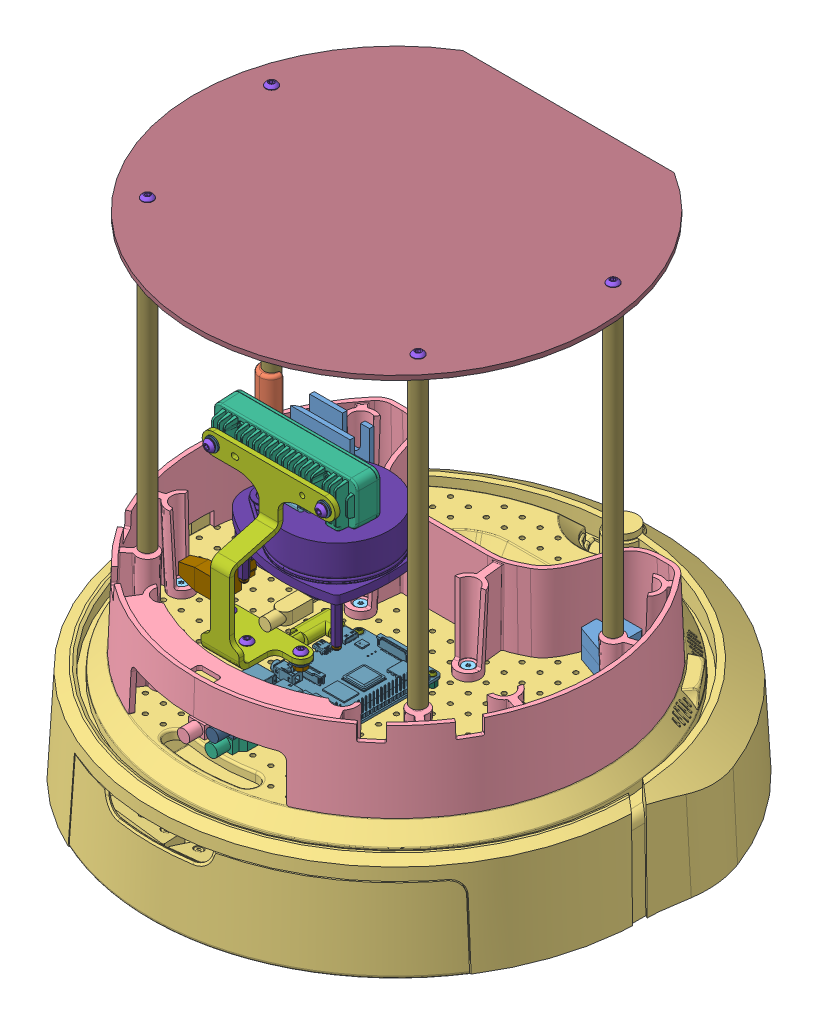
SolidWorks assembly mount_and_robot, configuration Default. Lengths in mm.
Overall size (344.21 352.66 342.43).
70 component instances, 28 part files, 2 mates.
Components (placement in the parent):
- BMP_camera_holder-1: BMP_camera_holder [Default] at (-168.9994 30.2674 -23.0245) x (-1 0 0) z (0 0 -1) size (60 40 38)
  - IR_camera-1: IR_camera [Default] at (-89.6669 -4.8675 17.6343) size (40 24 16)
  - pressure_sensor_holder-1: pressure_sensor_holder [Default] at (-44.6669 -4.8675 1.6343) x (-1 0 0) z (0 0 -1) size (50 40 22)
- turtlebot4_official.STEP-1: turtlebot4_official.STEP [Default] at (-17.5555 -120.5556 6.041) x (0.000609 0 -1) z (0 1 0) size (342.22 344 352.66)
  - 026292-OS_1__Item Name from PLM.STEP-1: 026292-OS_1__Item Name from PLM.STEP [Default] at (0 0 37.8855) x (0 1 0) z (1 0 0) size (344 96.08 342.22)
  - 025441_4_Riser Bracket-O275, Plastic, Black.STEP-1: 025441_4_Riser Bracket-O275, Plastic, Black.STEP [Default] at (0.0007 -0.0149 93.3855) size (229.59 273.19 53.38)
  - 025614_1_Screw, Cap, Flat Head-M3.5 X 10, Steal, Zinc Plate.STEP-1: 025614_1_Screw, Cap, Flat Head-M3.5 X 10, Steal, Zinc Plate.STEP [Default] at (72 96 92.546) x (0.995283 0.09701 0) z (0 0 1) size (7.3 7.3 10.01)
  - 025614_1_Screw, Cap, Flat Head-M3.5 X 10, Steal, Zinc Plate.STEP-2: 025614_1_Screw, Cap, Flat Head-M3.5 X 10, Steal, Zinc Plate.STEP [Default] at (12 36 92.546) x (0.967312 0.253588 0) z (0 0 1) size (7.3 7.3 10.01)
  - 025614_1_Screw, Cap, Flat Head-M3.5 X 10, Steal, Zinc Plate.STEP-3: 025614_1_Screw, Cap, Flat Head-M3.5 X 10, Steal, Zinc Plate.STEP [Default] at (12 -36 92.546) x (0.544294 -0.838895 0) z (0 0 1) size (7.3 7.3 10.01)
  - 025614_1_Screw, Cap, Flat Head-M3.5 X 10, Steal, Zinc Plate.STEP-4: 025614_1_Screw, Cap, Flat Head-M3.5 X 10, Steal, Zinc Plate.STEP [Default] at (72 -96 92.546) x (0.325351 0.945593 0) z (0 0 1) size (7.3 7.3 10.01)
  - 025614_1_Screw, Cap, Flat Head-M3.5 X 10, Steal, Zinc Plate.STEP-5: 025614_1_Screw, Cap, Flat Head-M3.5 X 10, Steal, Zinc Plate.STEP [Default] at (-36 -108 92.546) x (0.804099 0.594496 0) z (0 0 1) size (7.3 7.3 10.01)
  - 025614_1_Screw, Cap, Flat Head-M3.5 X 10, Steal, Zinc Plate.STEP-6: 025614_1_Screw, Cap, Flat Head-M3.5 X 10, Steal, Zinc Plate.STEP [Default] at (-96 -60 92.546) x (0.770543 0.637388 0) z (0 0 1) size (7.3 7.3 10.01)
  - 025614_1_Screw, Cap, Flat Head-M3.5 X 10, Steal, Zinc Plate.STEP-7: 025614_1_Screw, Cap, Flat Head-M3.5 X 10, Steal, Zinc Plate.STEP [Default] at (-96 60 92.546) x (0.764306 0.644854 0) z (0 0 1) size (7.3 7.3 10.01)
  - 025961_1_Camera, RGBD, Luxonis OAK-D-Pro.STEP-1: 025961_1_Camera, RGBD, Luxonis OAK-D-Pro.STEP [Default] at (-69.2695 -44.509 249.7055) x (0.00006 1 0) z (1 -0.00006 0) size (97.03 29.53 22.93)
  - 025426_6_Bracket, Camera, Aluminium Alloy.STEP-1: 025426_6_Bracket, Camera, Aluminium Alloy.STEP [Default] at (-118.0061 -0.0061 145.9555) x (1 -0.00006 0) z (0 0 1) size (36 89 99)
  - 025609_1_Screw, Cap, Round Head-M4x0.7 X 10, Stainless Steel Type 18-8, Black Oxide.STEP-1: 025609_1_Screw, Cap, Round Head-M4x0.7 X 10, Stainless Steel Type 18-8, Black Oxide.STEP [Default] at (-88.0075 -24.0078 145.3155) x (0.93747 0.348067 0) z (0 0 1) size (7.6 7.6 12.21)
  - 025609_1_Screw, Cap, Round Head-M4x0.7 X 10, Stainless Steel Type 18-8, Black Oxide.STEP-2: 025609_1_Screw, Cap, Round Head-M4x0.7 X 10, Stainless Steel Type 18-8, Black Oxide.STEP [Default] at (-100.0061 -0.0071 145.3155) x (0.79095 0.61188 0) z (0 0 1) size (7.6 7.6 12.21)
  - 025609_1_Screw, Cap, Round Head-M4x0.7 X 10, Stainless Steel Type 18-8, Black Oxide.STEP-3: 025609_1_Screw, Cap, Round Head-M4x0.7 X 10, Stainless Steel Type 18-8, Black Oxide.STEP [Default] at (-88.0046 23.9922 145.3155) x (0.731026 0.682349 0) z (0 0 1) size (7.6 7.6 12.21)
  - 010898_Nut, Hex-M4 x 0.7 X 3.2, Type 18-8 Stainless Steel.STEP-1: 010898_Nut, Hex-M4 x 0.7 X 3.2, Type 18-8 Stainless Steel.STEP [Default] at (-100.0061 -0.0071 141.8855) x (0.923728 0.383049 0) z (0 0 -1) size (8.09 8.1 3.22)
  - 025610_1_Washer, Flat-O4.3 X O9 X 0.9, Stainless Steel, Black Oxide.STEP-1: 025610_1_Washer, Flat-O4.3 X O9 X 0.9, Stainless Steel, Black Oxide.STEP [Default] at (-100.0061 -0.0071 144.3855) x (-0.923728 -0.383049 0) z (0 0 -1) size (9 9 0.9)
  - 010898_Nut, Hex-M4 x 0.7 X 3.2, Type 18-8 Stainless Steel.STEP-2: 010898_Nut, Hex-M4 x 0.7 X 3.2, Type 18-8 Stainless Steel.STEP [Default] at (-88.0075 -24.0078 141.8855) x (0.85131 0.524663 0) z (0 0 -1) size (8.09 8.1 3.22)
  - 025610_1_Washer, Flat-O4.3 X O9 X 0.9, Stainless Steel, Black Oxide.STEP-2: 025610_1_Washer, Flat-O4.3 X O9 X 0.9, Stainless Steel, Black Oxide.STEP [Default] at (-88.0075 -24.0078 144.3855) x (-0.85131 -0.524663 0) z (0 0 -1) size (9 9 0.9)
  - 010898_Nut, Hex-M4 x 0.7 X 3.2, Type 18-8 Stainless Steel.STEP-3: 010898_Nut, Hex-M4 x 0.7 X 3.2, Type 18-8 Stainless Steel.STEP [Default] at (-88.0046 23.9922 141.8855) x (0.777574 0.628792 0) z (0 0 -1) size (8.09 8.1 3.22)
  - 025610_1_Washer, Flat-O4.3 X O9 X 0.9, Stainless Steel, Black Oxide.STEP-3: 025610_1_Washer, Flat-O4.3 X O9 X 0.9, Stainless Steel, Black Oxide.STEP [Default] at (-88.0046 23.9922 144.3855) x (-0.777574 -0.628792 0) z (0 0 -1) size (9 9 0.9)
  - 025609_1_Screw, Cap, Round Head-M4x0.7 X 10, Stainless Steel Type 18-8, Black Oxide.STEP-4: 025609_1_Screw, Cap, Round Head-M4x0.7 X 10, Stainless Steel Type 18-8, Black Oxide.STEP [Default] at (-83.6246 37.4919 237.9555) x (0.000005 0.080023 0.996793) z (-1 0.00006 0) size (7.6 7.6 12.21)
  - 025609_1_Screw, Cap, Round Head-M4x0.7 X 10, Stainless Steel Type 18-8, Black Oxide.STEP-5: 025609_1_Screw, Cap, Round Head-M4x0.7 X 10, Stainless Steel Type 18-8, Black Oxide.STEP [Default] at (-83.6291 -37.5081 237.9555) x (0.000033 0.560382 -0.828234) z (-1 0.00006 0) size (7.6 7.6 12.21)
  - 025610_1_Washer, Flat-O4.3 X O9 X 0.9, Stainless Steel, Black Oxide.STEP-4: 025610_1_Washer, Flat-O4.3 X O9 X 0.9, Stainless Steel, Black Oxide.STEP [Default] at (-86.4246 37.4921 237.9555) x (-0.000007 -0.116927 -0.993141) z (1 -0.00006 0) size (9 9 0.9)
  - 025610_1_Washer, Flat-O4.3 X O9 X 0.9, Stainless Steel, Black Oxide.STEP-5: 025610_1_Washer, Flat-O4.3 X O9 X 0.9, Stainless Steel, Black Oxide.STEP [Default] at (-86.4291 -37.5079 237.9555) x (-0.000002 -0.035095 -0.999384) z (1 -0.00006 0) size (9 9 0.9)
  - 026387_1_Washer, Locking, Split-DIN 7980 M4 X 1.1, Steel, Black.STEP-1: 026387_1_Washer, Locking, Split-DIN 7980 M4 X 1.1, Steel, Black.STEP [Default] at (-87.5246 37.4921 237.9555) x (0 0.00006 -1) z (1 -0.00006 0) size (7 7 2.31)
  - 026387_1_Washer, Locking, Split-DIN 7980 M4 X 1.1, Steel, Black.STEP-2: 026387_1_Washer, Locking, Split-DIN 7980 M4 X 1.1, Steel, Black.STEP [Default] at (-87.5291 -37.5079 237.9555) x (0 0.00006 -1) z (1 -0.00006 0) size (7 7 2.31)
  - 025481_4_Standoff, Threaded, Round-Male-Female, M4 X 200, Aluminum.STEP-1: 025481_4_Standoff, Threaded, Round-Male-Female, M4 X 200, Aluminum.STEP [Default] at (30.6302 114.2957 241.9555) x (0 0 -1) z (-0.212288 0.977207 0) size (208 10 10)
  - 025481_4_Standoff, Threaded, Round-Male-Female, M4 X 200, Aluminum.STEP-2: 025481_4_Standoff, Threaded, Round-Male-Female, M4 X 200, Aluminum.STEP [Default] at (-76.0687 90.6411 241.9555) x (0 0 -1) z (-0.247385 -0.968917 0) size (208 10 10)
  - 025481_4_Standoff, Threaded, Round-Male-Female, M4 X 200, Aluminum.STEP-3: 025481_4_Standoff, Threaded, Round-Male-Female, M4 X 200, Aluminum.STEP [Default] at (30.6302 -114.2957 241.9555) x (0 0 -1) z (0.68149 -0.731827 0) size (208 10 10)
  - 025481_4_Standoff, Threaded, Round-Male-Female, M4 X 200, Aluminum.STEP-4: 025481_4_Standoff, Threaded, Round-Male-Female, M4 X 200, Aluminum.STEP [Default] at (-76.0687 -90.6411 241.9555) x (0 0 -1) z (0.57449 0.818512 0) size (208 10 10)
  - 025394_Plate, Sensor Integration.STEP-1: 025394_Plate, Sensor Integration.STEP [Default] at (0.0007 -0.0149 345.9555) size (250 270 3)
  - 025609_1_Screw, Cap, Round Head-M4x0.7 X 10, Stainless Steel Type 18-8, Black Oxide.STEP-6: 025609_1_Screw, Cap, Round Head-M4x0.7 X 10, Stainless Steel Type 18-8, Black Oxide.STEP [Default] at (30.6302 114.2957 345.0555) size (7.6 7.6 12.21)
  - 025609_1_Screw, Cap, Round Head-M4x0.7 X 10, Stainless Steel Type 18-8, Black Oxide.STEP-7: 025609_1_Screw, Cap, Round Head-M4x0.7 X 10, Stainless Steel Type 18-8, Black Oxide.STEP [Default] at (30.6302 -114.2957 345.0555) x (0.987351 0.158553 0) z (0 0 1) size (7.6 7.6 12.21)
  - 025609_1_Screw, Cap, Round Head-M4x0.7 X 10, Stainless Steel Type 18-8, Black Oxide.STEP-8: 025609_1_Screw, Cap, Round Head-M4x0.7 X 10, Stainless Steel Type 18-8, Black Oxide.STEP [Default] at (-76.0687 -90.6411 345.0555) x (0.959125 0.282984 0) z (0 0 1) size (7.6 7.6 12.21)
  - 025609_1_Screw, Cap, Round Head-M4x0.7 X 10, Stainless Steel Type 18-8, Black Oxide.STEP-9: 025609_1_Screw, Cap, Round Head-M4x0.7 X 10, Stainless Steel Type 18-8, Black Oxide.STEP [Default] at (-76.0687 90.6411 345.0555) x (0.928571 0.371154 0) z (0 0 1) size (7.6 7.6 12.21)
  - 024051_1_Computer, Single Board, SBC-Raspberry Pi 4, 2 GB.STEP-1: 024051_1_Computer, Single Board, SBC-Raspberry Pi 4, 2 GB.STEP [Default] at (-46.6082 -7.1031 99.1855) x (-1 0 0) z (0 1 0) size (89 19.93 58.4)
  - 025552_2_Standoff, Threaded, Hex - Male-Female, M2.5 X 5, Hex Size 4.5 mm, Aluminum.STEP-1: 025552_2_Standoff, Threaded, Hex - Male-Female, M2.5 X 5, Hex Size 4.5 mm, Aluminum.STEP [Default] at (-7.6082 17.3969 93.9355) x (0 0 -1) z (-0.895183 -0.445699 0) size (8.9 5.21 4.51)
  - 025552_2_Standoff, Threaded, Hex - Male-Female, M2.5 X 5, Hex Size 4.5 mm, Aluminum.STEP-2: 025552_2_Standoff, Threaded, Hex - Male-Female, M2.5 X 5, Hex Size 4.5 mm, Aluminum.STEP [Default] at (-65.6082 -31.6031 93.9455) x (0 0 -1) z (-0.813193 -0.581995 0) size (8.9 5.21 4.51)
  - 025552_2_Standoff, Threaded, Hex - Male-Female, M2.5 X 5, Hex Size 4.5 mm, Aluminum.STEP-3: 025552_2_Standoff, Threaded, Hex - Male-Female, M2.5 X 5, Hex Size 4.5 mm, Aluminum.STEP [Default] at (-7.6082 -31.6031 93.9355) x (0 0 -1) z (-0.813193 -0.581995 0) size (8.9 5.21 4.51)
  - 025552_2_Standoff, Threaded, Hex - Male-Female, M2.5 X 5, Hex Size 4.5 mm, Aluminum.STEP-4: 025552_2_Standoff, Threaded, Hex - Male-Female, M2.5 X 5, Hex Size 4.5 mm, Aluminum.STEP [Default] at (-65.6082 17.3969 93.9355) x (0 0 -1) z (-0.813193 -0.581995 0) size (8.9 5.21 4.51)
  - 025616_1_Screw, Cap, Round Head-M2.5x0.45 X 4, Stainless Steel Type 18-8, Black Oxide.STEP-1: 025616_1_Screw, Cap, Round Head-M2.5x0.45 X 4, Stainless Steel Type 18-8, Black Oxide.STEP [Default] at (-65.6082 17.3969 101.4755) x (-0.922007 -0.387173 0) z (0 0 1) size (4.5 4.5 5.5)
  - 025616_1_Screw, Cap, Round Head-M2.5x0.45 X 4, Stainless Steel Type 18-8, Black Oxide.STEP-2: 025616_1_Screw, Cap, Round Head-M2.5x0.45 X 4, Stainless Steel Type 18-8, Black Oxide.STEP [Default] at (-65.6082 -31.6031 101.4755) x (-0.848957 -0.528462 0) z (0 0 1) size (4.5 4.5 5.5)
  - 025616_1_Screw, Cap, Round Head-M2.5x0.45 X 4, Stainless Steel Type 18-8, Black Oxide.STEP-3: 025616_1_Screw, Cap, Round Head-M2.5x0.45 X 4, Stainless Steel Type 18-8, Black Oxide.STEP [Default] at (-7.6082 17.3969 101.4755) x (-0.774756 -0.63226 0) z (0 0 1) size (4.5 4.5 5.5)
  - 025616_1_Screw, Cap, Round Head-M2.5x0.45 X 4, Stainless Steel Type 18-8, Black Oxide.STEP-4: 025616_1_Screw, Cap, Round Head-M2.5x0.45 X 4, Stainless Steel Type 18-8, Black Oxide.STEP [Default] at (-7.6082 -31.6031 101.4755) x (-0.712449 -0.701724 0) z (0 0 1) size (4.5 4.5 5.5)
  - 025962_1_LIDAR, RPLidar A1M8, Slamtec.STEP-1: 025962_1_LIDAR, RPLidar A1M8, Slamtec.STEP [Default] at (-76.5474 -37.1117 145.9555) x (0.00006 1 0) z (1 -0.00006 0) size (97.35 55.07 71.45)
  - 026634_1_Screw, Cap, Socket Head-M2.5x0.45 X 6, Stainless Steel Type 316.STEP-1: 026634_1_Screw, Cap, Socket Head-M2.5x0.45 X 6, Stainless Steel Type 316.STEP [Default] at (-12.0078 -28.0124 142.8855) x (-0.959321 -0.282317 0) z (0 0 -1) size (4.7 4.7 7.5)
  - 026634_1_Screw, Cap, Socket Head-M2.5x0.45 X 6, Stainless Steel Type 316.STEP-2: 026634_1_Screw, Cap, Socket Head-M2.5x0.45 X 6, Stainless Steel Type 316.STEP [Default] at (-20.0036 41.9881 142.8855) x (-0.902424 -0.430849 0) z (0 0 -1) size (4.7 4.7 7.5)
  - 026634_1_Screw, Cap, Socket Head-M2.5x0.45 X 6, Stainless Steel Type 316.STEP-3: 026634_1_Screw, Cap, Socket Head-M2.5x0.45 X 6, Stainless Steel Type 316.STEP [Default] at (-60.0036 41.9905 142.8855) x (-0.840218 -0.542249 0) z (0 0 -1) size (4.7 4.7 7.5)
  - 026634_1_Screw, Cap, Socket Head-M2.5x0.45 X 6, Stainless Steel Type 316.STEP-4: 026634_1_Screw, Cap, Socket Head-M2.5x0.45 X 6, Stainless Steel Type 316.STEP [Default] at (-68.0078 -28.009 142.8855) x (-0.786015 -0.618207 0) z (0 0 -1) size (4.7 4.7 7.5)
  - Create3 Weight Pack_Item Name from PLM.STEP-1: Create3 Weight Pack_Item Name from PLM.STEP [Default] at (193.0236 145.8095 86.626) x (0.225602 -0.97422 0) z (0.959419 0.222174 -0.173648) size (48.09 14.03 30.89)
  - Create3 Weight Pack_Item Name from PLM.STEP-2: Create3 Weight Pack_Item Name from PLM.STEP [Default] at (193.0236 145.8095 95.626) x (0.225602 -0.97422 0) z (0.959419 0.222174 -0.173648) size (48.09 14.03 30.89)
  - Create3 Weight Pack_Item Name from PLM.STEP-3: Create3 Weight Pack_Item Name from PLM.STEP [Default] at (194.4529 -142.3863 109.1449) x (0.200558 0.979682 0) z (0.964798 -0.197511 0.173648) size (48.09 14.03 30.89)
  - Create3 Weight Pack_Item Name from PLM.STEP-4: Create3 Weight Pack_Item Name from PLM.STEP [Default] at (194.4529 -142.3863 118.1449) x (0.200558 0.979682 0) z (0.964798 -0.197511 0.173648) size (48.09 14.03 30.89)
  - 025740_1_Nut, Hex-M2.5 x 0.45 X 2.1, Steel Class 8, Zinc Plate.STEP-1: 025740_1_Nut, Hex-M2.5 x 0.45 X 2.1, Steel Class 8, Zinc Plate.STEP [Default] at (-65.6082 17.3969 89.6355) size (5.78 5.78 2.01)
  - 025740_1_Nut, Hex-M2.5 x 0.45 X 2.1, Steel Class 8, Zinc Plate.STEP-2: 025740_1_Nut, Hex-M2.5 x 0.45 X 2.1, Steel Class 8, Zinc Plate.STEP [Default] at (-65.6082 -31.6031 89.6355) size (5.78 5.78 2.01)
  - 025740_1_Nut, Hex-M2.5 x 0.45 X 2.1, Steel Class 8, Zinc Plate.STEP-3: 025740_1_Nut, Hex-M2.5 x 0.45 X 2.1, Steel Class 8, Zinc Plate.STEP [Default] at (-7.6082 -31.6031 89.6355) size (5.78 5.78 2.01)
  - 025740_1_Nut, Hex-M2.5 x 0.45 X 2.1, Steel Class 8, Zinc Plate.STEP-4: 025740_1_Nut, Hex-M2.5 x 0.45 X 2.1, Steel Class 8, Zinc Plate.STEP [Default] at (-7.6082 17.3969 89.6355) x (-0.997343 0.072845 0) z (0 0 1) size (5.78 5.78 2.01)
  - 025614_1_Screw, Cap, Flat Head-M3.5 X 10, Steal, Zinc Plate.STEP-8: 025614_1_Screw, Cap, Flat Head-M3.5 X 10, Steal, Zinc Plate.STEP [Default] at (-36 108 92.546) x (0.652394 0.75788 0) z (0 0 1) size (7.3 7.3 10.01)
  - 025944_2_Micro B ONLY.STEP-1: 025944_2_Micro B ONLY.STEP [Default] at (-205.6815 -7.5008 160.7555) x (0.00006 1 0) z (0 0 1) size (10 32.6 8.01)
  - 025944_2_USB A ONLY.STEP-1: 025944_2_USB A ONLY.STEP [Default] at (-240.7332 11.8969 103.9655) x (0 1 0) z (0 0 -1) size (16.5 47.05 8.45)
  - 025941_2_90 Deg ONLY.STEP-1: 025941_2_90 Deg ONLY.STEP [Default] at (-66.0541 -121.4542 215.4267) x (0 0 1) z (1 -0.00006 0) size (21.1 29 7)
  - 025941_2_USB A ONLY.STEP-1: 025941_2_USB A ONLY.STEP [Default] at (-242.0532 -6.1031 104.1255) x (0 -1 0) z (0 0 1) size (16.5 47.05 8.45)
  - 025942_1_90 Deg ONLY.STEP-1: 025942_1_90 Deg ONLY.STEP [Default] at (-155.8082 32.7969 101.5655) x (0 -1 0) z (0 0 -1) size (21.1 29 7)
  - 025942_1_USB C ONLY.STEP-1: 025942_1_USB C ONLY.STEP [Default] at (-220.2485 -60.2044 70.0453) x (0.000224 1 0) z (0 0 -1) size (13 36 7)
  - 025943_1_USB B ONLY.STEP-1: 025943_1_USB B ONLY.STEP [Default] at (-65.4395 138.7324 138.0655) x (1 -0.000138 0) z (0 0 1) size (28 26.85 13.5)
  - 025943_1_USB A ONLY.STEP-1: 025943_1_USB A ONLY.STEP [Default] at (-206.1782 -6.1031 112.6255) x (0 -1 0) z (0 0 1) size (16.5 47.05 8.45)
Mates (geometry in assembly coordinates):
- Concentric2: concentric aligned: cylinder of BMP_camera_holder-1/pressure_sensor_holder-1 through (-131.8325 65.3999 -24.6588) axis (0 -1 0) radius 5; cylinder of turtlebot4_official.STEP-1/025481_4_Standoff, Threaded, Round-Male-Female, M4 X 200, Aluminum.STEP-1 through (-131.8325 225.3999 -24.6588) axis (0 -1 0) radius 5
- Coincident4: coincident anti-aligned: plane of BMP_camera_holder-1/IR_camera-1 through (-119.3325 25.3999 -40.6588) normal (0 -1 0); plane of turtlebot4_official.STEP-1/025619_PCBA, Shell-shape-O273 X 230.STEP-1/025618_PCB, Shell-shape-O273 X 230.STEP-1 through (-17.5424 25.3999 6.0471) normal (0 1 0)
